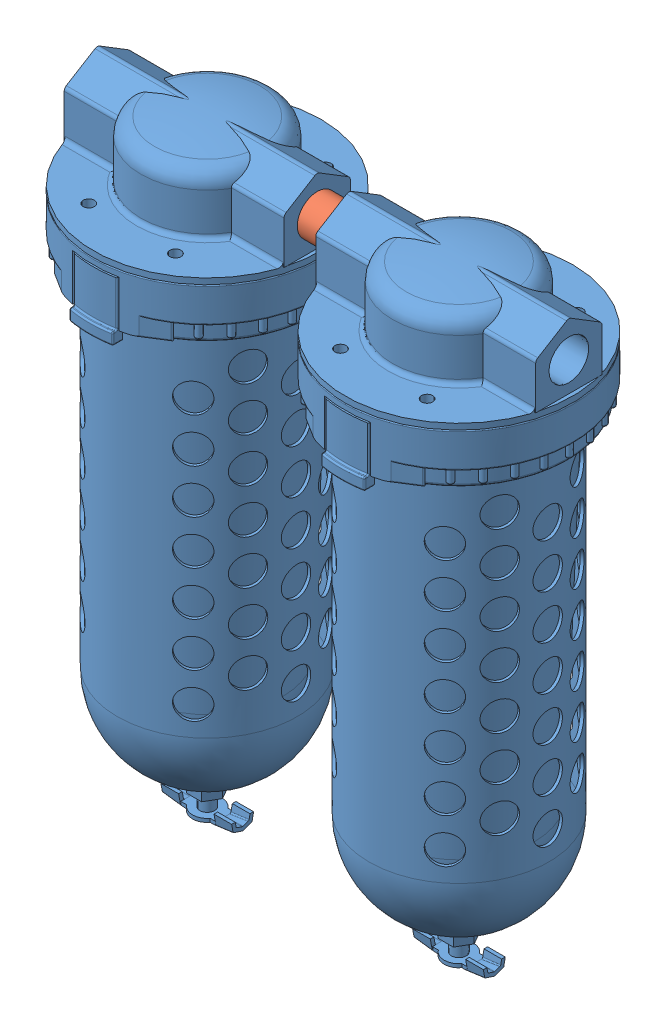
SolidWorks assembly ReadingTech_4P-060-P03-DCP, configuration Default. Lengths in mm.
Overall size (206.63 262.52 99.95).
3 component instances, 2 part files, 3 mates.
Components (placement in the parent):
- ReadingTech_3P-060-P03-P-1: ReadingTech_3P-060-P03-P [Default] at (-24.2032 -90.0119 4.9137) size (98.17 262.52 99.95)
- ReadingTech_3P-060-P03-P-2: ReadingTech_3P-060-P03-P [Default] at (84.2548 -90.0119 4.9137) size (98.17 262.52 99.95)
- ReadingTech- 60cfm_connector_.375in-1: ReadingTech- 60cfm_connector_.375in [Default] at (36.8838 125.8881 4.9137) x (0 1 0) z (0 0 1) size (17.14 13.72 17.14)
Mates (geometry in assembly coordinates):
- Coincident1: coincident anti-aligned: circle of ReadingTech_3P-060-P03-P-1; circle of ReadingTech- 60cfm_connector_.375in-1
- Coincident2: coincident aligned: circle of ReadingTech_3P-060-P03-P-2; circle of ReadingTech- 60cfm_connector_.375in-1
- Coincident3: coincident aligned: plane of ReadingTech_3P-060-P03-P-1 through (23.1678 113.1881 19.2012) normal (0 0 1); plane of ReadingTech_3P-060-P03-P-2 through (131.6258 113.1881 19.2012) normal (0 0 1)
